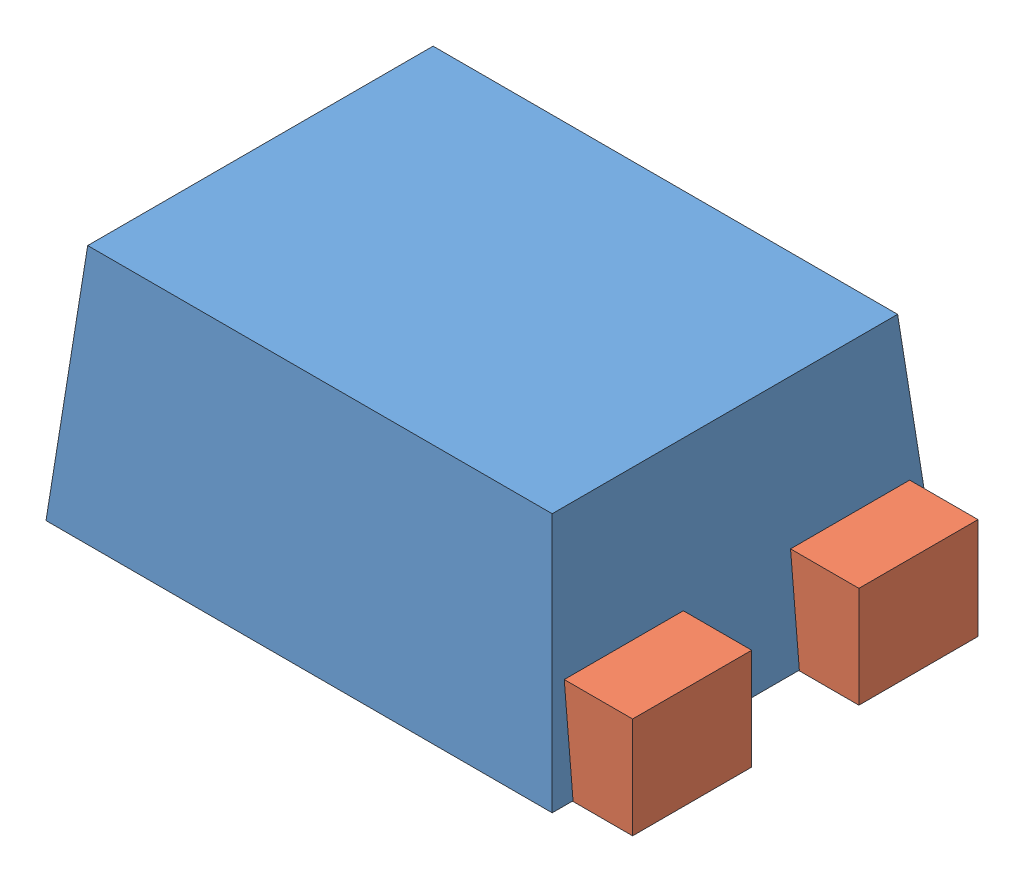
SolidWorks assembly Assem3, configuration Default. Lengths in mm.
Overall size (1.05 0.4 0.65).
4 component instances, 3 part files, 7 mates.
Components (placement in the parent):
- Body-1: Body [Default] at origin size (0.85 0.4 0.65)
- SP-1: SP [Default] at (0.355 -0.001 -0.19) size (0.34 0.17 0.2)
- SP-2: SP [Default] at (0.355 -0.001 0.19) size (0.34 0.17 0.2)
- BP-1: BP [Default] at (-0.355 -0.001 0) size (0.34 0.17 0.26)
Mates (geometry in assembly coordinates):
- Distance4: distance = 0.001 mm: plane of SP-1 through (0.355 -0.001 -0.19) normal (0 -1 0); plane of assembly
- Parallel1: parallel: plane of SP-1 through (0.525 0.169 -0.09) normal (1 0 0); plane of assembly through (0 0 0) normal (1 0 0)
- Distance1: distance = 0.525 mm: plane of SP-1 through (0.525 0.169 -0.09) normal (1 0 0); plane of assembly through (0 0 0) normal (1 0 0)
- Distance2: distance = 0.19 mm: plane of SP-1 through (0.355 -0.001 -0.19) normal (0 0 1); plane of assembly through (0 0 0) normal (0 0 1)
- Coincident5: coincident: plane of ? through (-0.355 0 0) normal (0 0 1)
- Distance3: distance = 0.525 mm: plane of BP-1 through (-0.525 0.169 0.13) normal (-1 0 0); plane of assembly
- Distance5: distance = 0.001 mm: plane of BP-1 through (-0.355 -0.001 0) normal (0 -1 0); plane of assembly
